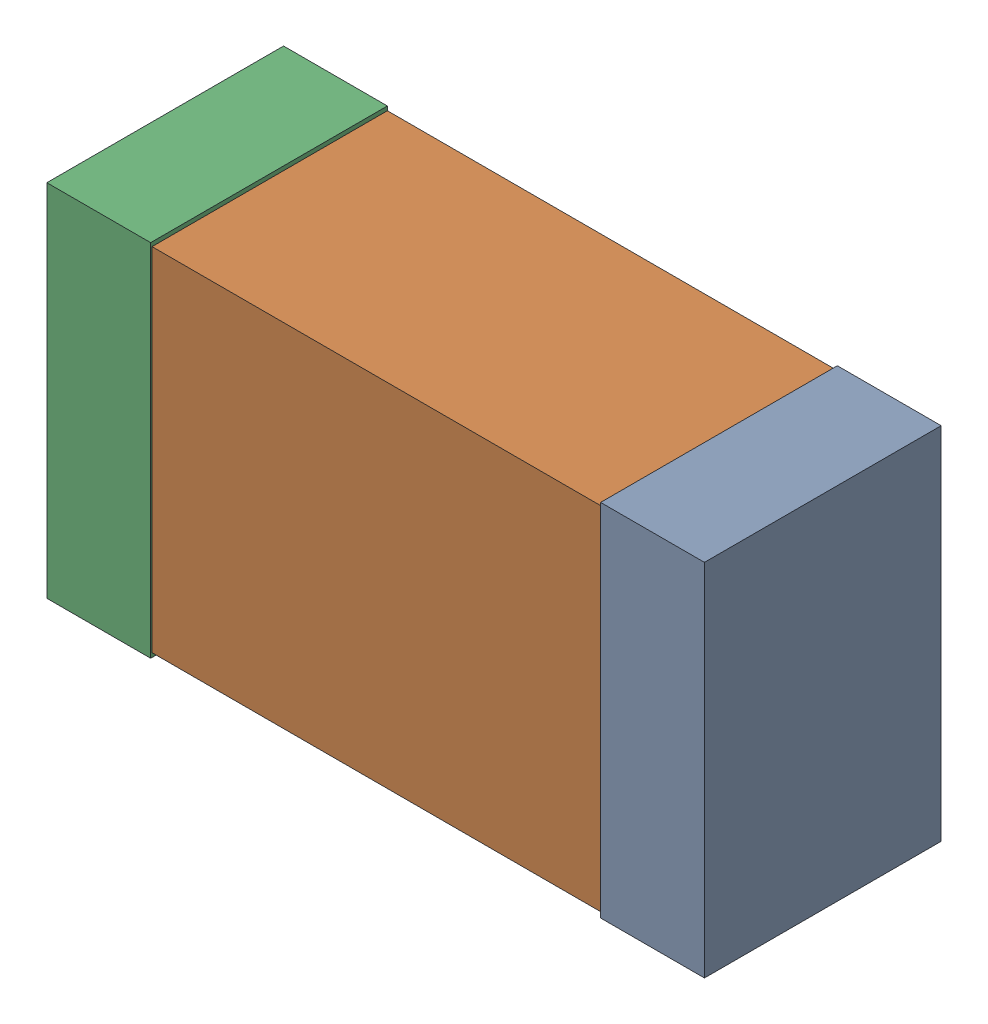
SolidWorks assembly R9Kanaloa_v2.0.0_GPIO_b, configuration Default. Lengths in mm.
Overall size (2.38 1.3 0.85).
6 component instances, 2 part files, 0 mates.
Components (placement in the parent):
- 352877648-1: 352877648 [Default] at (146.796 118.872 0) size (0.38 1.3 0.85)
  - Extruded_14-1: Extruded_14 [Default] at origin size (0.38 1.3 0.85)
- 352877904-1: 352877904 [Default] at (145.796 118.872 0) size (2.2 1.27 0.85)
  - Extruded_18-1: Extruded_18 [Default] at origin size (2.2 1.27 0.85)
- 352877648-2: 352877648 [Default] at (144.796 118.872 0) size (0.38 1.3 0.85)
  - Extruded_14-1: Extruded_14 [Default] at origin size (0.38 1.3 0.85)
